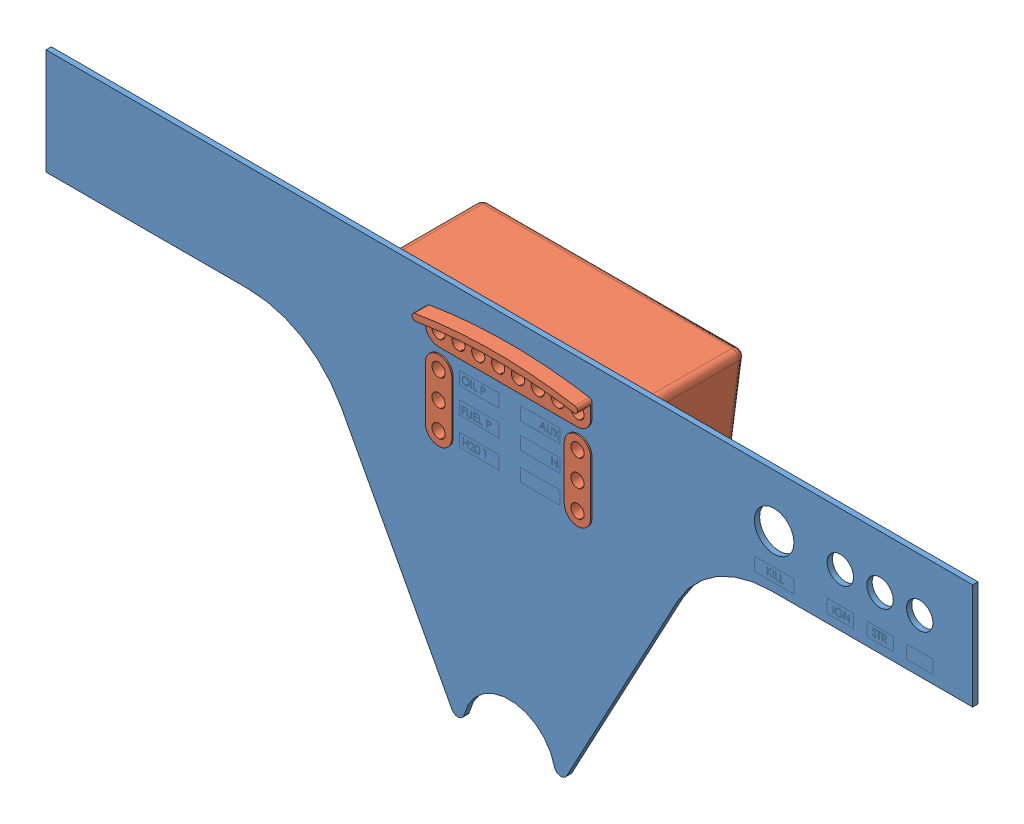
SolidWorks assembly dash assy, configuration Default. Lengths in mm.
Overall size (444.5 231.01 57.15).
2 component instances, 2 part files, 3 mates.
Components (placement in the parent):
- dash-1: dash [Default] at origin size (444.5 178.35 2.54)
- PCB box-1: PCB box [Default] at (0 136.525 -3.175) size (126.11 76.2 57.15)
Mates (geometry in assembly coordinates):
- Coincident1: coincident anti-aligned: plane of dash-1 through (0 0 0) normal (0 0 -1); plane of PCB box-1 through (0 136.525 0) normal (0 0 1)
- Coincident2: coincident aligned: plane of dash-1 through (0 0 0) normal (1 0 0); plane of PCB box-1 through (0 136.525 -3.175) normal (1 0 0)
- Distance1: distance = 6.35 mm aligned: plane of PCB box-1 through (0 174.625 -41.275) normal (0 1 0); plane of dash-1 through (0 180.975 2.54) normal (0 1 0)
